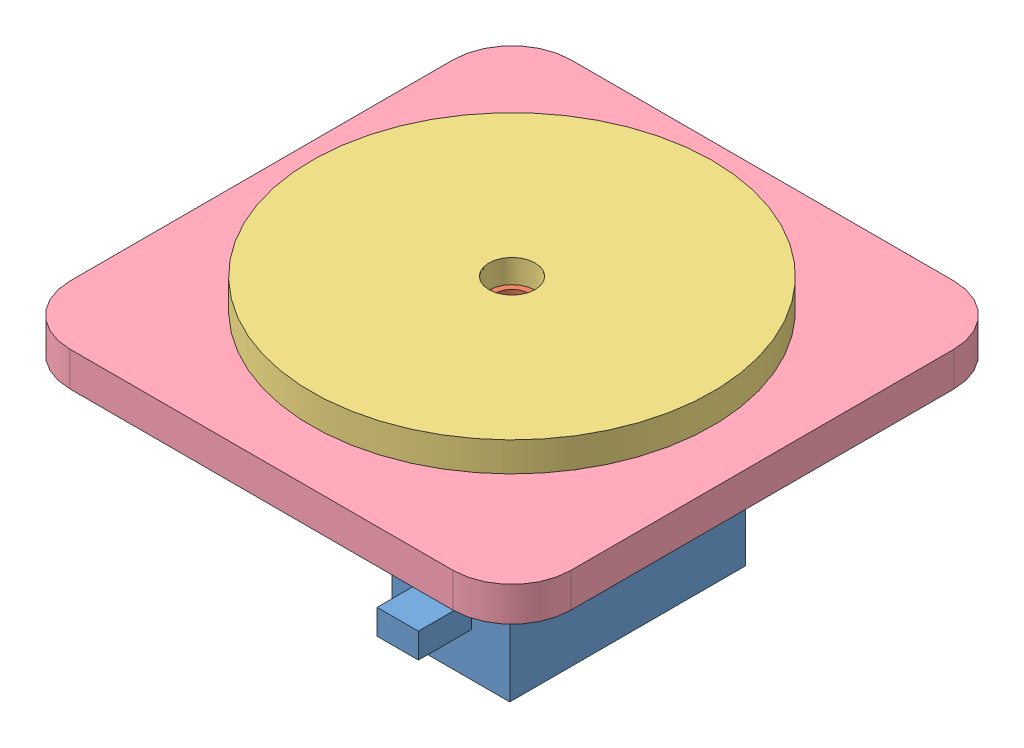
SolidWorks assembly PanTilt, configuration Default. Lengths in mm.
Overall size (85 52.35 85).
4 component instances, 4 part files, 10 mates.
Components (placement in the parent):
- D3015v2-1: D3015v2 [Default] at (7.7183 28.7801 43.0761) x (0 0 -1) z (0 -1 0) size (56.5 20 45.8)
- RoundServoHornv2-1: RoundServoHornv2 [Default] at (27.7712 54.6301 62.2608) x (-0.005514 0 -0.999985) z (0 1 0) size (20.8 20.8 5.55)
- Pan Head-1: Pan Head [Default] at (27.7712 56.8801 62.2608) x (-0.005514 0 -0.999985) z (0 1 0) size (68 68 5)
- Base Plate-1: Base Plate [Default] at (0 55.1801 0) x (-1 0 0) z (0 -1 0) size (85 85 5.85)
Mates (geometry in assembly coordinates):
- Coincident4: coincident anti-aligned: plane of D3015v2-1 through (17.7183 54.3301 52.6961) normal (0 1 0); plane of RoundServoHornv2-1 through (17.7183 54.3301 52.6961) normal (0 -1 0)
- Concentric1: concentric anti-aligned: circle of D3015v2-1; circle of RoundServoHornv2-1
- InPlace3: in place: plane of ? through (17.7183 56.8801 52.6961) normal (0 1 0); plane of ? through (0 56.8801 0) normal (0 1 0); moOrthogonalPlaneRef_w of ? through (17.7183 56.8801 52.6961) normal (0 1 0); plane of ? through (0 56.8801 0) normal (0 0 -1); plane of ? through (17.7183 56.8801 52.6961) normal (0 1 0); plane of ? through (0 56.8801 0) normal (1 0 0); plane of RoundServoHornv2-1 through (17.7183 56.8801 52.6961) normal (0 1 0); unknown of Pan Head-1
- Coincident9: coincident aligned: plane of RoundServoHornv2-1; plane of Pan Head-1
- Coincident10: coincident aligned: moOrthogonalPlaneRef_w of RoundServoHornv2-1; plane of Pan Head-1 through (27.7712 56.8801 62.2608) normal (-0.999985 0 0.005514)
- Coincident11: coincident anti-aligned: moOrthogonalPlaneRef_w of RoundServoHornv2-1; plane of Pan Head-1 through (27.7712 56.8801 62.2608) normal (-0.005514 0 -0.999985)
- InPlace4: in place: plane of Base Plate-1 through (0 55.1801 0) normal (0 -1 0); plane of Base Plate-1 through (0 55.1801 0) normal (0 0 -1); plane of Base Plate-1 through (0 55.1801 0) normal (-1 0 0); unknown of Base Plate-1
- Coincident12: coincident aligned: plane of Base Plate-1; plane of assembly
- Coincident13: coincident aligned: plane of Base Plate-1 through (0 55.1801 0) normal (0 0 -1); moOrthogonalPlaneRef_w of assembly
- Coincident14: coincident anti-aligned: plane of Base Plate-1 through (0 55.1801 0) normal (-1 0 0); moOrthogonalPlaneRef_w of assembly
